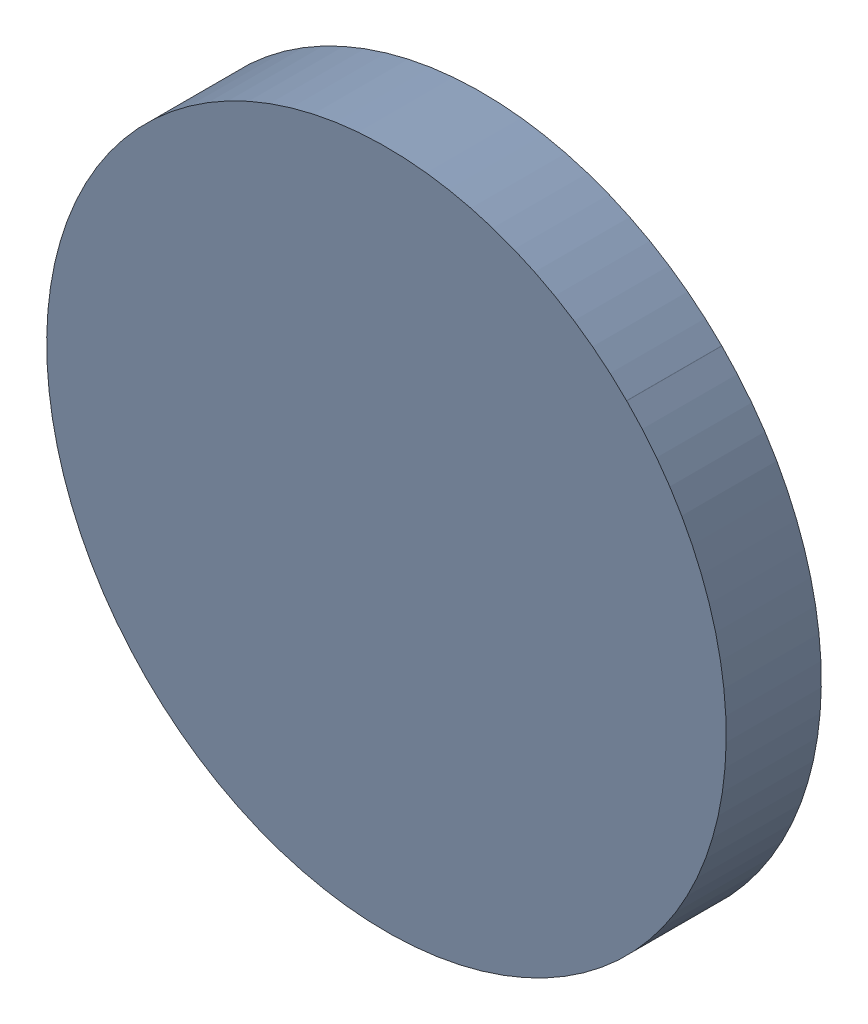
SolidWorks assembly Track (31mm,40mm)(31mm,40mm) on Top Layer, configuration Predeterminado. Lengths in mm.
Overall size (0.25 0.25 0.04).
2 component instances, 1 part files, 0 mates.
Components (placement in the parent):
- Track (31mm,40mm)(31mm,40mm) on Top Layer-1-1: Track (31mm,40mm)(31mm,40mm) on Top Layer-1 [Predeterminado] at (-68.317 -44.187 -0.0457) size (0.25 0.25 0.04)
  - Track (31mm,40mm)(31mm,40mm) on Top Layer-Part-1-1: Track (31mm,40mm)(31mm,40mm) on Top Layer-Part-1 [Predeterminado] at origin size (0.25 0.25 0.04)
